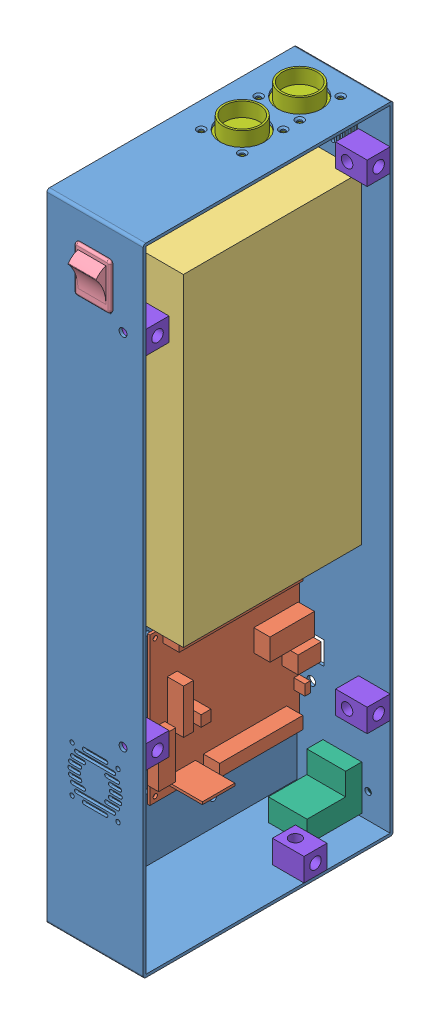
SolidWorks assembly electronics_assy, configuration Default. Lengths in mm.
Overall size (67 451.67 186.77).
14 component instances, 9 part files, 39 mates.
Components (placement in the parent):
- electronics_case_TAZ_5_2-1: electronics_case_TAZ_5_2 [Default] at origin size (67 443 174)
- S-400-24-1: S-400-24 [Default] at (2 58 -17.5) x (0 1 0) z (0 0 -1) size (215 50 115) (hidden)
- RAMBo-1: RAMBo [Default] at (6 -126.935 -28.93) x (0 0 1) z (1 0 0) size (109.47 102.87 29.21)
- SE-450-24-1: SE-450-24 [Default] at (2 62 -18) x (0 1 0) z (0 0 -1) size (238 50 124)
- R5BBLKREDFF2-1: R5BBLKREDFF2 [Default] at (33.275 185.4 87) x (0 -1 0) z (-1 0 0) size (32.1 25.97 25.2)
- 40mm_Fan-1: 40mm_Fan [Default] at (33.5 -119.5 74.5) size (40 40 10.5)
- PF0030-63-1: PF0030-63 [Default] at (33.65 -201.95 -87) x (-1 0 0) z (0 0 -1) size (44 34.1 44)
- A106308-ND-1: A106308-ND [Default] at (32 230.17 -57) x (0 -1 0) z (0 0 1) size (27.18 36.45 36.45)
- A106308-ND-2: A106308-ND [Default] at (32 230.17 -17) x (0 -1 0) z (0 0 1) size (27.18 36.45 36.45)
- mount_block-1: mount_block [Default] at (67 194.5 -69) x (-1 0 0) z (0 -1 0) size (22 16 16)
- mount_block-2: mount_block [Default] at (67 169.5 85) x (-1 0 0) z (0 -1 0) size (22 16 16)
- mount_block-3: mount_block [Default] at (67 -80.5 85) x (-1 0 0) z (0 -1 0) size (22 16 16)
- mount_block-4: mount_block [Default] at (67 -135.5 -69) x (-1 0 0) z (0 -1 0) size (22 16 16)
- mount_block-5: mount_block [Default] at (67 -203.5 -41) x (-1 0 0) z (0 0 1) size (22 16 16)
Mates (geometry in assembly coordinates):
- Coincident1: coincident anti-aligned: plane of electronics_case_TAZ_5_2-1 through (2 -221.5 87) normal (1 0 0); plane of S-400-24-1 through (2 -49.5 -75) normal (-1 0 0)
- Distance1: distance = 170 mm anti-aligned: plane of S-400-24-1 through (52 -49.5 40) normal (0 -1 0); plane of electronics_case_TAZ_5_2-1 through (67 -219.5 85) normal (0 1 0)
- Distance3: distance = 10 mm anti-aligned: plane of S-400-24-1 through (52 -49.5 -75) normal (0 0 -1); plane of electronics_case_TAZ_5_2-1 through (67 -219.5 -85) normal (0 0 1)
- Distance4: distance = 6 mm aligned: plane of RAMBo-1 through (6 -75.5 -81) normal (-1 0 0); plane of electronics_case_TAZ_5_2-1 through (0 -221.5 87) normal (-1 0 0)
- Distance5: distance = 6 mm aligned: plane of electronics_case_TAZ_5_2-1 through (2 221.5 -87) normal (0 0 -1); plane of RAMBo-1 through (7.778 -178.37 -81) normal (0 0 -1)
- Coincident8: coincident anti-aligned: plane of electronics_case_TAZ_5_2-1 through (2 -221.5 87) normal (1 0 0); plane of SE-450-24-1 through (2 -50.5 -80) normal (-1 0 0)
- Concentric1: concentric anti-aligned: circle of electronics_case_TAZ_5_2-1; cylinder of SE-450-24-1 through (7 -17 -42.5) axis (-1 0 0) radius 2
- Concentric2: concentric anti-aligned: circle of electronics_case_TAZ_5_2-1; cylinder of SE-450-24-1 through (7 -17 7.5) axis (-1 0 0) radius 2
- Distance10: distance = 295 mm anti-aligned: plane of electronics_case_TAZ_5_2-1 through (67 219.5 -85) normal (0 -1 0); plane of RAMBo-1 through (7.778 -75.5 -81) normal (0 1 0)
- Coincident9: coincident anti-aligned: plane of electronics_case_TAZ_5_2-1 through (2 221.5 87) normal (0 0 1); plane of R5BBLKREDFF2-1 through (43.875 171.35 87) normal (0 0 -1)
- Coincident10: coincident anti-aligned: plane of electronics_case_TAZ_5_2-1 through (22.425 199 82) normal (1 0 0); plane of R5BBLKREDFF2-1 through (22.425 199 69.8) normal (-1 0 0)
- Coincident11: coincident anti-aligned: plane of electronics_case_TAZ_5_2-1 through (22.425 199 82) normal (0 -1 0); plane of R5BBLKREDFF2-1 through (22.425 199 87) normal (0 1 0)
- Coincident12: coincident anti-aligned: plane of electronics_case_TAZ_5_2-1 through (67 219.5 85) normal (0 0 -1); plane of 40mm_Fan-1 through (49.5 -103.5 85) normal (0 0 1)
- Distance11: distance = 13.5 mm aligned: plane of 40mm_Fan-1 through (53.5 -103.5 85) normal (1 0 0); plane of electronics_case_TAZ_5_2-1 through (67 221.5 87) normal (1 0 0)
- Distance12: distance = 80 mm anti-aligned: plane of 40mm_Fan-1 through (17.5 -139.5 85) normal (0 -1 0); plane of electronics_case_TAZ_5_2-1 through (67 -219.5 85) normal (0 1 0)
- Coincident15: coincident anti-aligned: plane of electronics_case_TAZ_5_2-1 through (2 221.5 -87) normal (0 0 -1); plane of PF0030-63-1 through (47.65 -218 -87) normal (0 0 1)
- Concentric3: concentric aligned: cylinder of electronics_case_TAZ_5_2-1 through (51.65 -201.95 -82) axis (0 0 -1) radius 2.25; cylinder of PF0030-63-1 through (51.65 -201.95 -89) axis (0 0 -1) radius 1.7
- Concentric4: concentric aligned: cylinder of electronics_case_TAZ_5_2-1 through (15.65 -201.95 -82) axis (0 0 -1) radius 2.25; cylinder of PF0030-63-1 through (15.65 -201.95 -89) axis (0 0 -1) radius 1.7
- Coincident16: coincident anti-aligned: plane of electronics_case_TAZ_5_2-1 through (67 219.5 -85) normal (0 -1 0); plane of A106308-ND-1 through (45.335 219.5 -57) normal (0 1 0)
- Concentric5: concentric aligned: cylinder of electronics_case_TAZ_5_2-1 through (32 211.5 -57) axis (0 1 0) radius 15.365; cylinder of A106308-ND-1 through (32 230.17 -57) axis (0 1 0) radius 13.335
- Concentric6: concentric aligned: cylinder of electronics_case_TAZ_5_2-1 through (46.29 221.5 -71.29) axis (0 1 0) radius 1.632; cylinder of A106308-ND-1 through (46.29 209.5 -71.29) axis (0 1 0) radius 1.6
- Coincident17: coincident anti-aligned: plane of electronics_case_TAZ_5_2-1 through (67 219.5 -85) normal (0 -1 0); plane of A106308-ND-2 through (45.335 219.5 -17) normal (0 1 0)
- Concentric7: concentric aligned: cylinder of electronics_case_TAZ_5_2-1 through (32 211.5 -17) axis (0 1 0) radius 15.365; cylinder of A106308-ND-2 through (32 230.17 -17) axis (0 1 0) radius 13.335
- Concentric8: concentric aligned: cylinder of electronics_case_TAZ_5_2-1 through (17.71 221.5 -2.71) axis (0 1 0) radius 1.632; cylinder of A106308-ND-2 through (17.71 209.5 -2.71) axis (0 1 0) radius 1.6
- Coincident18: coincident aligned: plane of electronics_case_TAZ_5_2-1 through (67 221.5 87) normal (1 0 0); plane of mount_block-1 through (67 178.5 -69) normal (1 0 0)
- Coincident19: coincident anti-aligned: plane of electronics_case_TAZ_5_2-1 through (67 -219.5 -85) normal (0 0 1); plane of mount_block-1 through (67 178.5 -85) normal (0 0 -1)
- Distance13: distance = 25 mm anti-aligned: plane of mount_block-1 through (67 194.5 -85) normal (0 1 0); plane of electronics_case_TAZ_5_2-1 through (67 219.5 -85) normal (0 -1 0)
- Coincident21: coincident anti-aligned: plane of electronics_case_TAZ_5_2-1 through (67 -219.5 85) normal (0 1 0); plane of mount_block-5 through (67 -219.5 -25) normal (0 -1 0)
- Coincident22: coincident aligned: plane of electronics_case_TAZ_5_2-1 through (67 221.5 87) normal (1 0 0); plane of mount_block-5 through (67 -203.5 -25) normal (1 0 0)
- Distance14: distance = 110 mm anti-aligned: plane of electronics_case_TAZ_5_2-1 through (67 219.5 85) normal (0 0 -1); plane of mount_block-5 through (67 -219.5 -25) normal (0 0 1)
- Coincident24: coincident anti-aligned: plane of electronics_case_TAZ_5_2-1 through (67 -219.5 -85) normal (0 0 1); plane of mount_block-4 through (67 -151.5 -85) normal (0 0 -1)
- Coincident25: coincident aligned: plane of electronics_case_TAZ_5_2-1 through (67 221.5 87) normal (1 0 0); plane of mount_block-4 through (67 -151.5 -69) normal (1 0 0)
- Distance15: distance = 70 mm aligned: plane of mount_block-4 through (67 -151.5 -85) normal (0 -1 0); plane of electronics_case_TAZ_5_2-1 through (2 -221.5 87) normal (0 -1 0)
- Coincident27: coincident anti-aligned: plane of electronics_case_TAZ_5_2-1 through (67 219.5 85) normal (0 0 -1); plane of mount_block-3 through (67 -96.5 85) normal (0 0 1)
- Coincident28: coincident aligned: plane of electronics_case_TAZ_5_2-1 through (67 221.5 87) normal (1 0 0); plane of mount_block-3 through (67 -96.5 85) normal (1 0 0)
- Coincident30: coincident anti-aligned: plane of electronics_case_TAZ_5_2-1 through (67 219.5 85) normal (0 0 -1); plane of mount_block-2 through (67 153.5 85) normal (0 0 1)
- Coincident31: coincident aligned: plane of electronics_case_TAZ_5_2-1 through (67 221.5 87) normal (1 0 0); plane of mount_block-2 through (67 153.5 85) normal (1 0 0)
- Distance16: distance = 52 mm aligned: plane of mount_block-2 through (67 169.5 69) normal (0 1 0); plane of electronics_case_TAZ_5_2-1 through (2 221.5 87) normal (0 1 0)
- Distance17: distance = 125 mm aligned: plane of mount_block-3 through (67 -96.5 69) normal (0 -1 0); plane of electronics_case_TAZ_5_2-1 through (2 -221.5 87) normal (0 -1 0)
